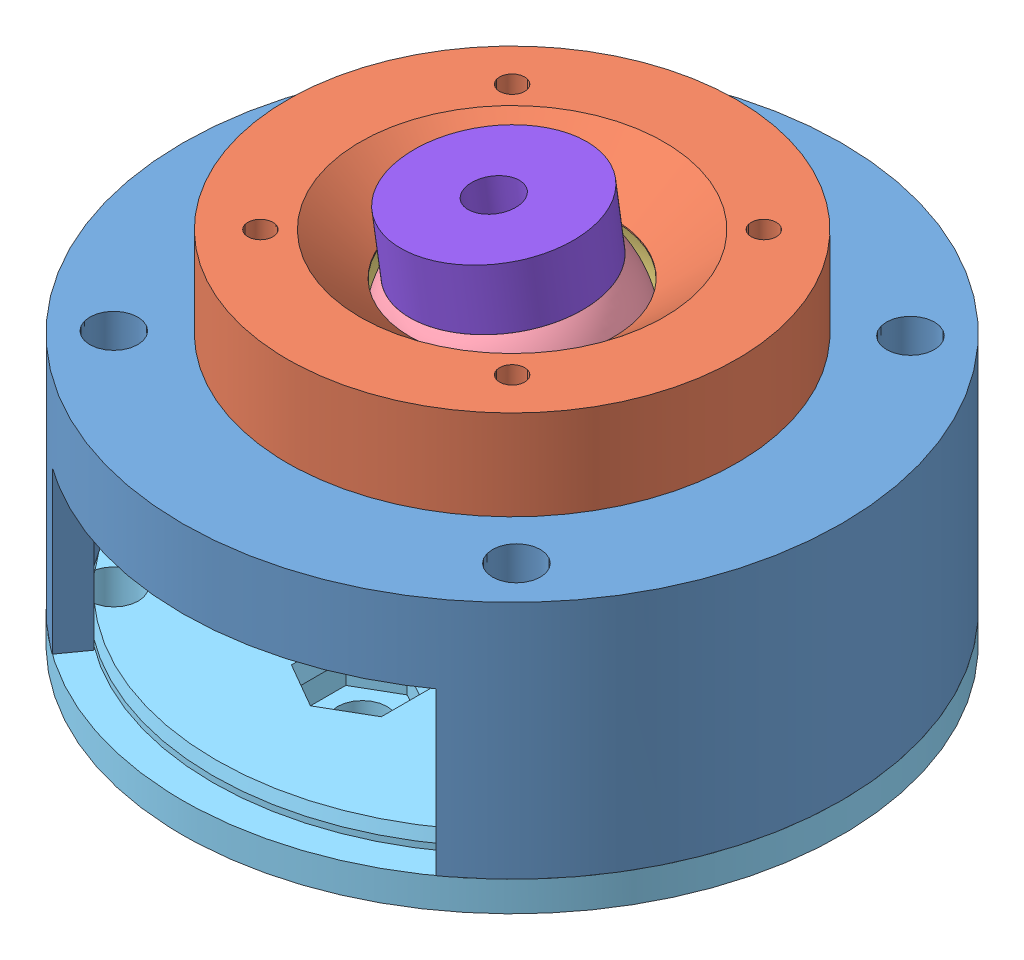
SolidWorks assembly gimbal GE25 ES-2RS, configuration По умолчанию. Lengths in mm.
Overall size (110 79.37 110).
10 component instances, 9 part files, 18 mates.
Components (placement in the parent):
- gimbal_housing_testbed_gimbal01a-1: gimbal_housing_testbed_gimbal01a [По умолчанию] at origin size (110 40 110)
- gimbal_housing_p2_gimbal02-1: gimbal_housing_p2_gimbal02 [По умолчанию] at (0 40 0) size (75 15 75)
- GE25 ES-2RS-2: GE25 ES-2RS [По умолчанию] at (0 39.9 0) x (0.53961 0 0.841915) z (-0.841915 0 0.53961) size (42 23.9 42) (flexible)
  - outer_ring-1: outer_ring [По умолчанию] at origin size (42 15.8 42)
  - inner_ring-1: inner_ring [По умолчанию] x (-0.024889 0.109354 -0.993691) z (-0.999658 0.005313 0.025623) size (35.07 20 35.07)
- gimbal_housing_bottom_p1_gimbal03-1: gimbal_housing_bottom_p1_gimbal03 [По умолчанию] at (0 -5 0) x (1 0 -0.000014) z (0.000014 0 1) size (110 20.5 110)
- gimbal_cjmcu_frame_gimbal05-1: gimbal_cjmcu_frame_gimbal05 [По умолчанию] at (0 -1 0) x (1 0 -0.000014) z (0.000014 0 1) size (48 14 25)
- CJMCU-93-1: CJMCU-93 [По умолчанию] at (-5.2 13 0.0001) x (1 0 -0.000014) z (0.000014 0 1) size (28.4 3.1 22)
- gimbal_stick_connector_p1_gimbal06-1: gimbal_stick_connector_p1_gimbal06 [По умолчанию] at (1.3135 24.9902 -0.9858) x (0.490655 0.100451 -0.865544) z (0.866943 0.043544 0.496502) size (29 35 29)
- gimbal_stick_connector_p2_gimbal06-1: gimbal_stick_connector_p2_gimbal06 [По умолчанию] at (1.7513 20.0202 -1.3144) x (-0.542828 -0.102929 0.833513) z (-0.835267 -0.03731 -0.548578) size (29 10 29)
Mates (geometry in assembly coordinates):
- Concentric1: concentric anti-aligned: cylinder of gimbal_housing_testbed_gimbal01a-1 through (0 32 0) axis (0 1 0) radius 21.1; cylinder of gimbal_housing_p2_gimbal02-1 through (0 55 0) axis (0 -1 0) radius 17
- Concentric2: concentric aligned: cylinder of gimbal_housing_testbed_gimbal01a-1 through (21 0 21) axis (0 1 0) radius 2; cylinder of gimbal_housing_p2_gimbal02-1 through (21 40 21) axis (0 1 0) radius 2.1
- Coincident1: coincident anti-aligned: plane of gimbal_housing_testbed_gimbal01a-1 through (0 40 0) normal (0 1 0); plane of gimbal_housing_p2_gimbal02-1 through (0 40 0) normal (0 -1 0)
- Concentric3: concentric aligned: cylinder of gimbal_housing_testbed_gimbal01a-1 through (0 32 0) axis (0 1 0) radius 21.1; cylinder of GE25 ES-2RS-2/outer_ring-1 through (0 47.8 0) axis (0 1 0) radius 21
- Coincident2: coincident anti-aligned: plane of gimbal_housing_testbed_gimbal01a-1 through (0 32 0) normal (0 1 0); plane of GE25 ES-2RS-2/outer_ring-1 through (15.1545 32 -9.713) normal (0 -1 0)
- Concentric4: concentric aligned: cylinder of gimbal_housing_testbed_gimbal01a-1 through (0 40 0) axis (0 -1 0) radius 55; cylinder of gimbal_housing_bottom_p1_gimbal03-1 through (0 0 0) axis (0 -1 0) radius 55
- Concentric5: concentric anti-aligned: cylinder of gimbal_housing_testbed_gimbal01a-1 through (33.5917 0 -32.8724) axis (0 1 0) radius 4; cylinder of gimbal_housing_bottom_p1_gimbal03-1 through (33.5917 3 -32.8724) axis (0 -1 0) radius 4.1
- Coincident3: coincident anti-aligned: plane of gimbal_housing_testbed_gimbal01a-1 through (0 0 0) normal (0 -1 0); plane of gimbal_housing_bottom_p1_gimbal03-1 through (0 0 0) normal (0 1 0)
- Concentric6: concentric anti-aligned: cylinder of gimbal_housing_bottom_p1_gimbal03-1 through (20.0001 -17.5 8.9997) axis (0 1 0) radius 1.5; cylinder of gimbal_cjmcu_frame_gimbal05-1 through (20.0001 13 8.9997) axis (0 -1 0) radius 1.6
- Concentric7: concentric anti-aligned: circle of gimbal_housing_bottom_p1_gimbal03-1; cylinder of gimbal_cjmcu_frame_gimbal05-1 through (-20.0001 13 -8.9997) axis (0 -1 0) radius 1.6
- Coincident4: coincident anti-aligned: plane of gimbal_housing_bottom_p1_gimbal03-1 through (0 -1 0) normal (0 1 0); plane of gimbal_cjmcu_frame_gimbal05-1 through (0 -1 0) normal (0 -1 0)
- Concentric10: concentric anti-aligned: cylinder of gimbal_housing_bottom_p1_gimbal03-1 through (0 0 0) axis (0 -1 0) radius 55; cylinder of CJMCU-93-1 through (0 13 0) axis (0 1 0) radius 6.4
- Coincident5: coincident anti-aligned: plane of gimbal_cjmcu_frame_gimbal05-1 through (0 13 0) normal (0 1 0); plane of CJMCU-93-1 through (-5.2 13 0.0001) normal (0 -1 0)
- Parallel2: parallel aligned: plane of gimbal_cjmcu_frame_gimbal05-1 through (23.9998 3 -12.5003) normal (-0.000014 0 -1); plane of CJMCU-93-1 through (8.9998 14.5 -11.0001) normal (-0.000014 0 -1)
- Concentric11: concentric aligned: cylinder of GE25 ES-2RS-2/inner_ring-1 through (1.4189 23.7928 -1.065) axis (0.087563 -0.993989 -0.06572) radius 12.5; cylinder of gimbal_stick_connector_p1_gimbal06-1 through (-0.8756 49.8399 0.6572) axis (0.087563 -0.993989 -0.06572) radius 12.35
- Coincident6: coincident anti-aligned: plane of GE25 ES-2RS-2/inner_ring-1 through (6.1368 49.7735 11.0047) normal (-0.087563 0.993989 0.06572); plane of gimbal_stick_connector_p1_gimbal06-1 through (-0.8756 49.8399 0.6572) normal (0.087563 -0.993989 -0.06572)
- Concentric12: concentric anti-aligned: cylinder of gimbal_stick_connector_p1_gimbal06-1 through (-0.8756 49.8399 0.6572) axis (0.087563 -0.993989 -0.06572) radius 12.35; cylinder of gimbal_stick_connector_p2_gimbal06-1 through (1.401 23.9962 -1.0515) axis (-0.087563 0.993989 0.06572) radius 12.5
- Coincident8: coincident anti-aligned: plane of GE25 ES-2RS-2/inner_ring-1 through (7.8881 29.8937 9.6903) normal (0.087563 -0.993989 -0.06572); plane of gimbal_stick_connector_p2_gimbal06-1 through (0.8756 29.9601 -0.6572) normal (-0.087563 0.993989 0.06572)
